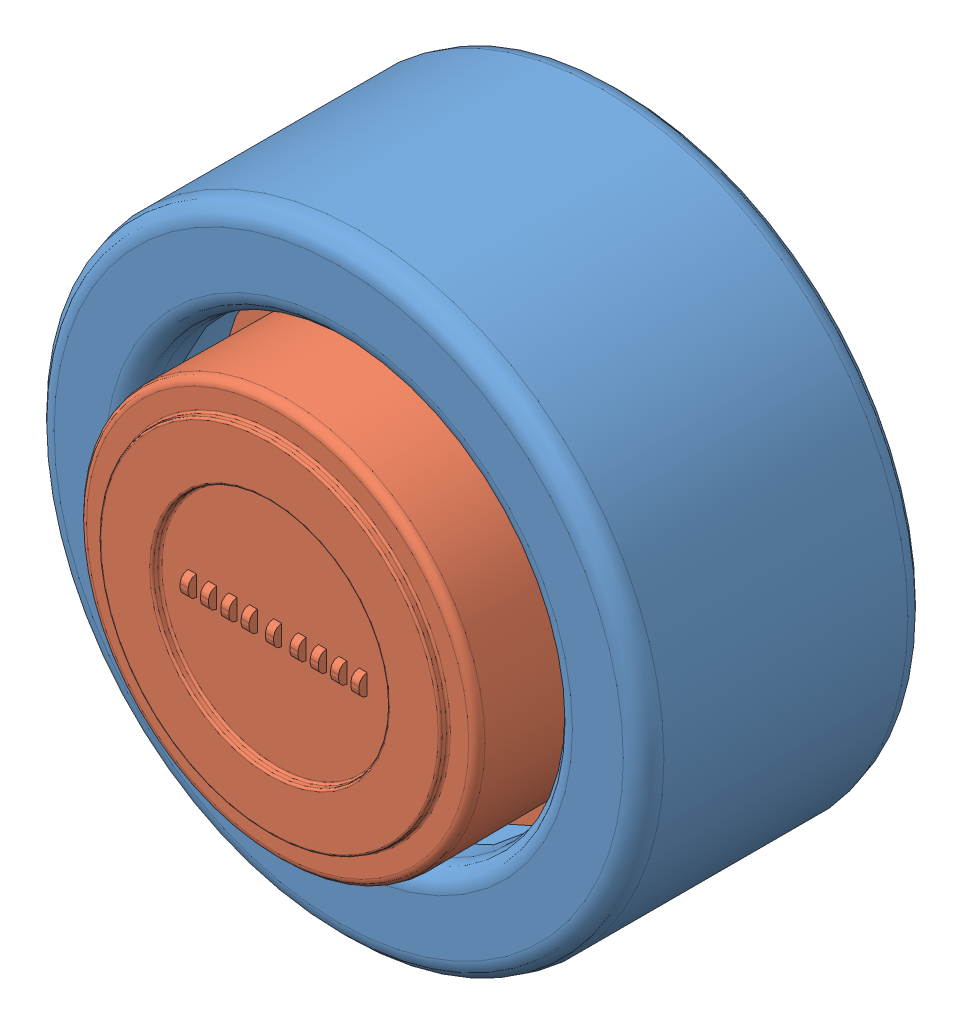
SolidWorks assembly 装配体2, configuration Default. Lengths in mm.
Overall size (15 15 8.69).
2 component instances, 2 part files, 0 mates.
Components (placement in the parent):
- 充电座V1.0-磁吸接头固定-1: 充电座V1.0-磁吸接头固定 [Default] at (4.1467 8.5462 8.2922) size (15 15 7)
- 充电座V1.0-磁吸接头-2: 充电座V1.0-磁吸接头 [Default] at (4.1392 8.4682 16.786) size (11 11 5.2)
